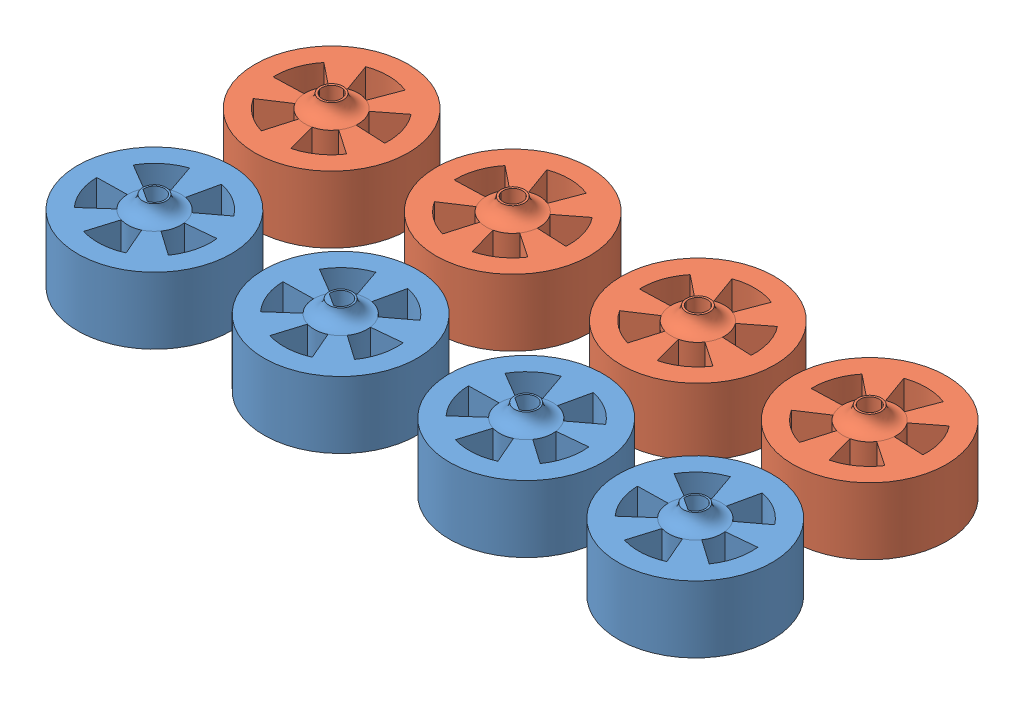
SolidWorks assembly All Wheels, configuration Default. Lengths in mm.
Overall size (112.44 12 54.01).
8 component instances, 2 part files, 8 mates.
Components (placement in the parent):
- Driver Wheel-1: Driver Wheel [Default] at (4.036 0 24.1189) x (-0.837169 0 -0.546944) z (0 1 0) size (23 23 12)
- Driver Wheel-2: Driver Wheel [Default] at (-21.6616 0 23.7594) x (-0.837169 0 -0.546944) z (0 1 0) size (23 23 12)
- Idler Wheel-1: Idler Wheel [Default] at (-21.4228 10 -1.7425) x (1 0 0) z (0 -1 0) size (23 23 12)
- Idler Wheel-3: Idler Wheel [Default] at (4.3672 10 -1.7023) x (1 0 0) z (0 -1 0) size (23 23 12)
- Idler Wheel-4: Idler Wheel [Default] at (-76.415 10 -1.8227) x (1 0 0) z (0 -1 0) size (23 23 12)
- Driver Wheel-3: Driver Wheel [Default] at (-76.5733 0 24.5763) x (-0.837169 0 -0.546944) z (0 1 0) size (23 23 12)
- Idler Wheel-5: Idler Wheel [Default] at (-49.4533 10 -2.0169) x (1 0 0) z (0 -1 0) size (23 23 12)
- Driver Wheel-4: Driver Wheel [Default] at (-49.0815 0 24.1524) x (-0.837169 0 -0.546944) z (0 1 0) size (23 23 12)
Mates (geometry in assembly coordinates):
- Coincident6: coincident: plane of Idler Wheel-1 through (-21.4228 0 -1.7425) normal (0 -1 0); plane of assembly through (0 0 0) normal (0 1 0)
- Coincident7: coincident: plane of Idler Wheel-3 through (4.3672 0 -1.7023) normal (0 -1 0); plane of assembly through (0 0 0) normal (0 1 0)
- Coincident8: coincident: plane of Driver Wheel-2 through (-21.6616 0 23.7594) normal (0 -1 0); plane of assembly through (0 0 0) normal (0 1 0)
- Coincident9: coincident: plane of Driver Wheel-1 through (4.036 0 24.1189) normal (0 -1 0); plane of assembly through (0 0 0) normal (0 1 0)
- Coincident10: coincident: plane of Driver Wheel-4 through (-49.0815 0 24.1524) normal (0 -1 0); plane of assembly through (0 0 0) normal (0 1 0)
- Coincident11: coincident: plane of Driver Wheel-3 through (-76.5733 0 24.5763) normal (0 -1 0); plane of assembly
- Coincident12: coincident: plane of Idler Wheel-4 through (-76.415 0 -1.8227) normal (0 -1 0); plane of assembly
- Coincident13: coincident: plane of Idler Wheel-5 through (-49.4533 0 -2.0169) normal (0 -1 0); plane of assembly
